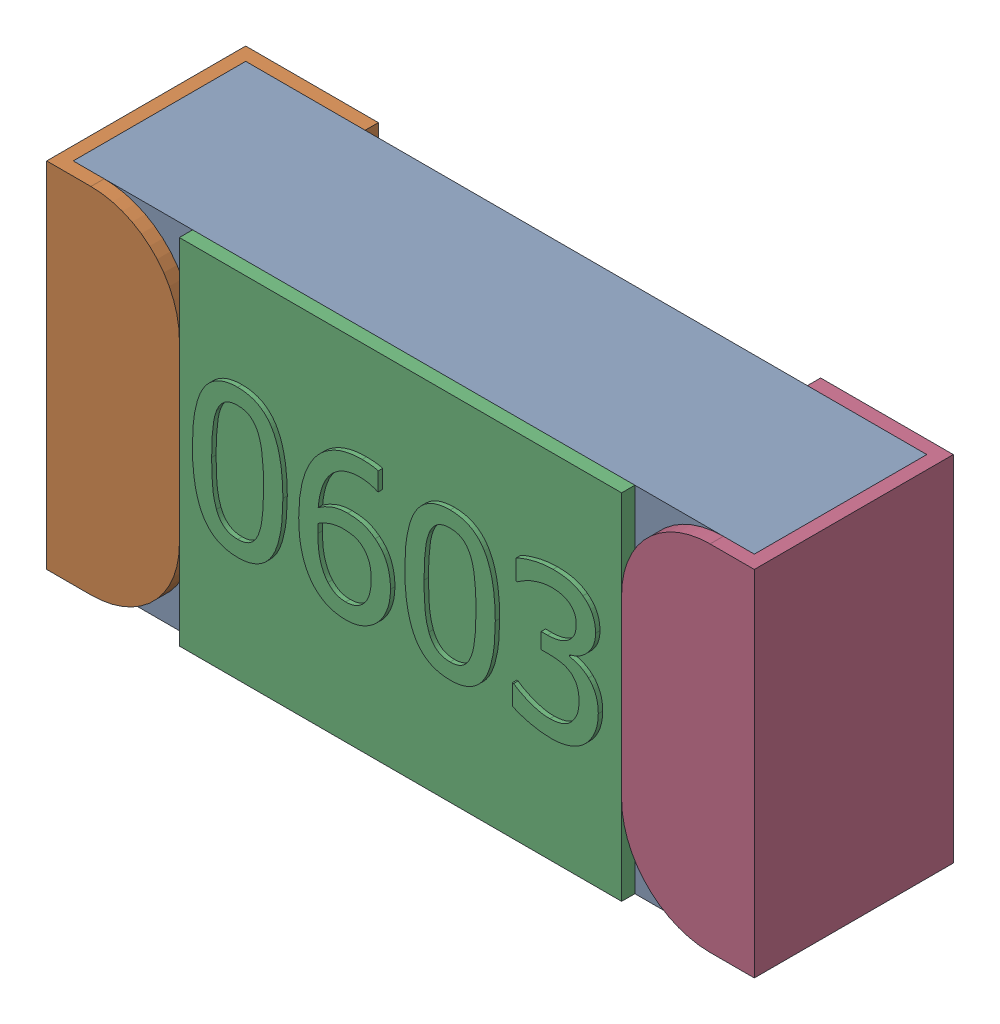
SolidWorks assembly Open CASCADE STEP translator 6.8 48.3, configuration 默认. Lengths in mm.
Overall size (1.6 0.8 0.46).
5 component instances, 3 part files, 0 mates.
Components (placement in the parent):
- 0603_RES-1: 0603_RES [默认] at (14.7305 76.9641 0) x (1 0 0) z (0 -1 0) size (1.6 0.46 0.8)
  - Capsule-1: Capsule [默认] at origin size (1.54 0.39 0.8)
  - Encapsulation-1: Encapsulation [默认] at (-0.8 -0.03 0.4) size (0.3 0.45 0.8)
  - TopCover-1: TopCover [默认] at (0 0.39 0) size (1 0.04 0.8)
  - Encapsulation-2: Encapsulation [默认] at (0.8 -0.03 -0.4) x (-1 0 0) z (0 0 -1) size (0.3 0.45 0.8)
